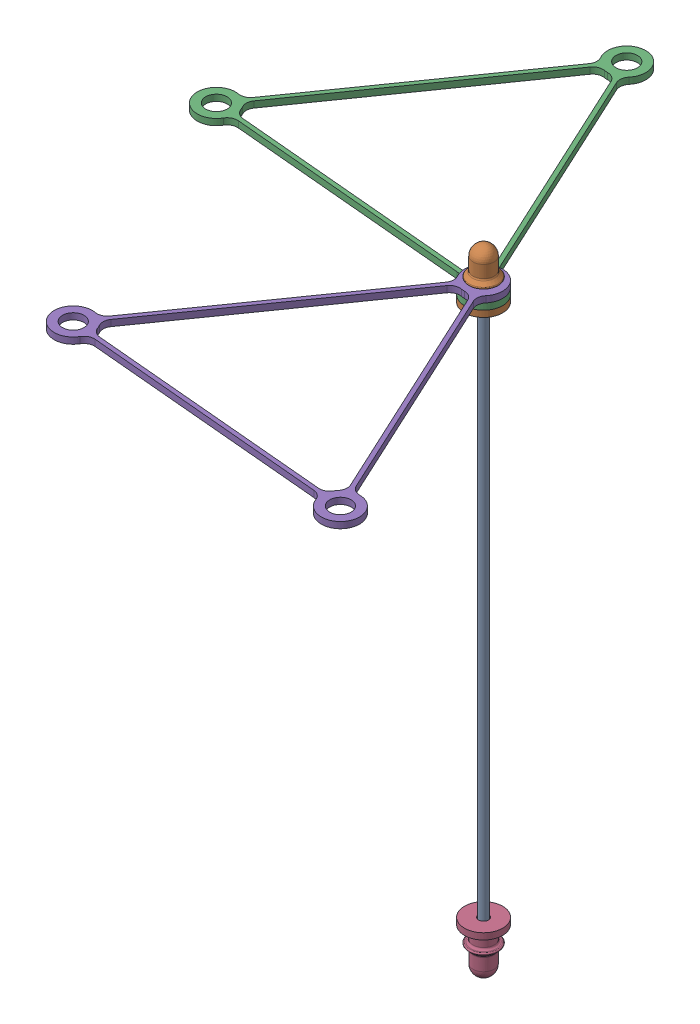
SolidWorks assembly rod_end_assembly, configuration Default. Lengths in mm.
Overall size (114.76 151 140.35).
5 component instances, 3 part files, 8 mates.
Components (placement in the parent):
- tensegrity_rods_2mm_130mm-1: tensegrity_rods_2mm_130mm [Default] at (-9.7784 0.0666 5.1146) size (2 147 2)
- rod_end_cap-1: rod_end_cap [Default] at (-9.7784 63.5666 5.1146) x (-0.583889 0 0.811833) z (-0.811833 0 -0.583889) size (9.1 12 9.1)
- tensegrity_cable_section-1: tensegrity_cable_section [Default] at (-42.9365 65.8166 -18.1924) x (0.996035 0 0.088957) z (-0.088957 0 0.996035) size (79.3 1.5 69.89)
- rod_end_cap-2: rod_end_cap [Default] at (-9.7784 -63.4334 5.1146) x (-0.891214 0 0.453584) z (0.453584 0 0.891214) size (9.1 12 9.1)
- tensegrity_cable_section-2: tensegrity_cable_section [Default] at (-13.3838 67.3166 45.484) x (0.996035 0 0.088957) z (-0.088957 0 0.996035) size (79.3 1.5 69.89)
Mates (geometry in assembly coordinates):
- Concentric1: concentric aligned: cylinder of tensegrity_rods_2mm_130mm-1 through (-9.7784 73.5666 5.1146) axis (0 -1 0) radius 1; cylinder of rod_end_cap-1 through (-9.7784 75.5666 5.1146) axis (0 -1 0) radius 2.5
- Coincident1: coincident anti-aligned: plane of tensegrity_rods_2mm_130mm-1 through (-9.7784 73.5666 5.1146) normal (0 1 0); plane of rod_end_cap-1 through (-9.7784 73.5666 5.1146) normal (0 -1 0)
- Concentric2: concentric aligned: cylinder of rod_end_cap-1 through (-9.7784 75.5666 5.1146) axis (0 -1 0) radius 2.5; cylinder of tensegrity_cable_section-1 through (-9.7784 66.5666 5.1146) axis (0 -1 0) radius 2.55
- Coincident2: coincident anti-aligned: plane of rod_end_cap-1 through (-9.7784 65.0666 5.1146) normal (0 1 0); plane of tensegrity_cable_section-1 through (-79.7 65.0666 -1.1301) normal (0 -1 0)
- Concentric3: concentric anti-aligned: cylinder of tensegrity_rods_2mm_130mm-1 through (-9.7784 73.5666 5.1146) axis (0 -1 0) radius 1; cylinder of rod_end_cap-2 through (-9.7784 -75.4334 5.1146) axis (0 1 0) radius 2.5
- Coincident3: coincident anti-aligned: plane of tensegrity_rods_2mm_130mm-1 through (-9.7784 -73.4334 5.1146) normal (0 -1 0); plane of rod_end_cap-2 through (-9.7784 -73.4334 5.1146) normal (0 1 0)
- Concentric4: concentric anti-aligned: circle of tensegrity_cable_section-1; cylinder of tensegrity_cable_section-2 through (-9.7784 68.0666 5.1146) axis (0 -1 0) radius 2.55
- Coincident4: coincident aligned: plane of tensegrity_cable_section-1 through (-79.7 66.5666 -1.1301) normal (0 1 0); circle of tensegrity_cable_section-2
